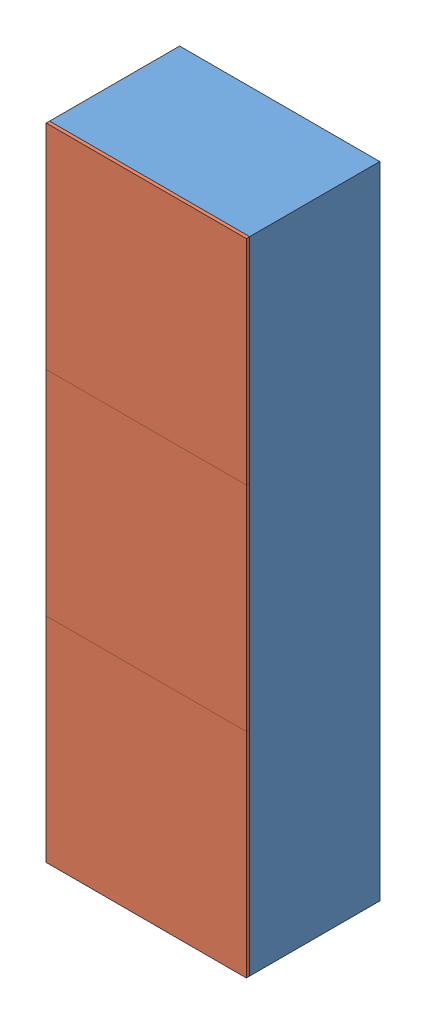
SolidWorks assembly Schrank-R, configuration Standard. Lengths in mm.
Overall size (600 1920 400).
6 component instances, 3 part files, 15 mates.
Components (placement in the parent):
- Schrank-Korpus-1: Schrank-Korpus [Standard] at (68.177 -29.4401 1725) size (600 1920 390)
- Türe-1: Türe [Standard] at (68.177 -669.4401 2115) size (600 640 10)
- Türe-2: Türe [Standard] at (68.177 -29.4401 2115) size (600 640 10)
- Türe-3: Türe [Standard] at (68.177 610.5599 2115) size (600 640 10)
- Regalbrett-1: Regalbrett [Standard] at (68.177 -354.4401 2095) x (1 0 0) z (0 1 0) size (560 360 10)
- Regalbrett-2: Regalbrett [Standard] at (68.177 285.5599 2095) x (1 0 0) z (0 1 0) size (560 360 10)
Mates (geometry in assembly coordinates):
- Deckungsgleich1: coincident anti-aligned: plane of Schrank-Korpus-1 through (68.177 -29.4401 1735) normal (0 0 1); plane of Regalbrett-2 through (68.177 285.5599 1735) normal (0 0 -1)
- Deckungsgleich2: coincident anti-aligned: plane of Schrank-Korpus-1 through (-211.823 910.5599 2115) normal (1 0 0); plane of Regalbrett-2 through (-211.823 290.5599 1735) normal (-1 0 0)
- Deckungsgleich3: coincident anti-aligned: plane of Schrank-Korpus-1 through (68.177 -29.4401 1735) normal (0 0 1); plane of Regalbrett-1 through (68.177 -354.4401 1735) normal (0 0 -1)
- Deckungsgleich4: coincident anti-aligned: plane of Schrank-Korpus-1 through (-211.823 910.5599 2115) normal (1 0 0); plane of Regalbrett-1 through (-211.823 -349.4401 1735) normal (-1 0 0)
- Deckungsgleich5: coincident aligned: plane of Schrank-Korpus-1 through (368.177 -989.4401 1735) normal (1 0 0); plane of Türe-1 through (368.177 -989.4401 2125) normal (1 0 0)
- Deckungsgleich6: coincident aligned: plane of Schrank-Korpus-1 through (-231.823 -989.4401 1735) normal (0 -1 0); plane of Türe-1 through (-231.823 -989.4401 2125) normal (0 -1 0)
- Deckungsgleich7: coincident aligned: plane of Schrank-Korpus-1 through (368.177 -989.4401 1735) normal (1 0 0); plane of Türe-2 through (368.177 -349.4401 2125) normal (1 0 0)
- Deckungsgleich8: coincident anti-aligned: plane of Türe-1 through (-231.823 -349.4401 2125) normal (0 1 0); plane of Türe-2 through (-231.823 -349.4401 2125) normal (0 -1 0)
- Deckungsgleich9: coincident aligned: plane of Schrank-Korpus-1 through (368.177 -989.4401 1735) normal (1 0 0); plane of Türe-3 through (368.177 290.5599 2125) normal (1 0 0)
- Deckungsgleich10: coincident anti-aligned: plane of Türe-2 through (-231.823 290.5599 2125) normal (0 1 0); plane of Türe-3 through (-231.823 290.5599 2125) normal (0 -1 0)
- Deckungsgleich11: coincident anti-aligned: plane of Schrank-Korpus-1 through (68.177 -29.4401 2115) normal (0 0 1); plane of Türe-1 through (68.177 -669.4401 2115) normal (0 0 -1)
- Deckungsgleich12: coincident aligned: plane of Türe-1 through (-231.823 -349.4401 2125) normal (0 1 0); plane of Regalbrett-1 through (-211.823 -349.4401 1735) normal (0 1 0)
- Deckungsgleich13: coincident anti-aligned: plane of Schrank-Korpus-1 through (68.177 -29.4401 2115) normal (0 0 1); plane of Türe-2 through (68.177 -29.4401 2115) normal (0 0 -1)
- Deckungsgleich14: coincident aligned: plane of Türe-2 through (-231.823 290.5599 2125) normal (0 1 0); plane of Regalbrett-2 through (-211.823 290.5599 1735) normal (0 1 0)
- Deckungsgleich15: coincident anti-aligned: plane of Schrank-Korpus-1 through (68.177 -29.4401 2115) normal (0 0 1); plane of Türe-3 through (68.177 610.5599 2115) normal (0 0 -1)
